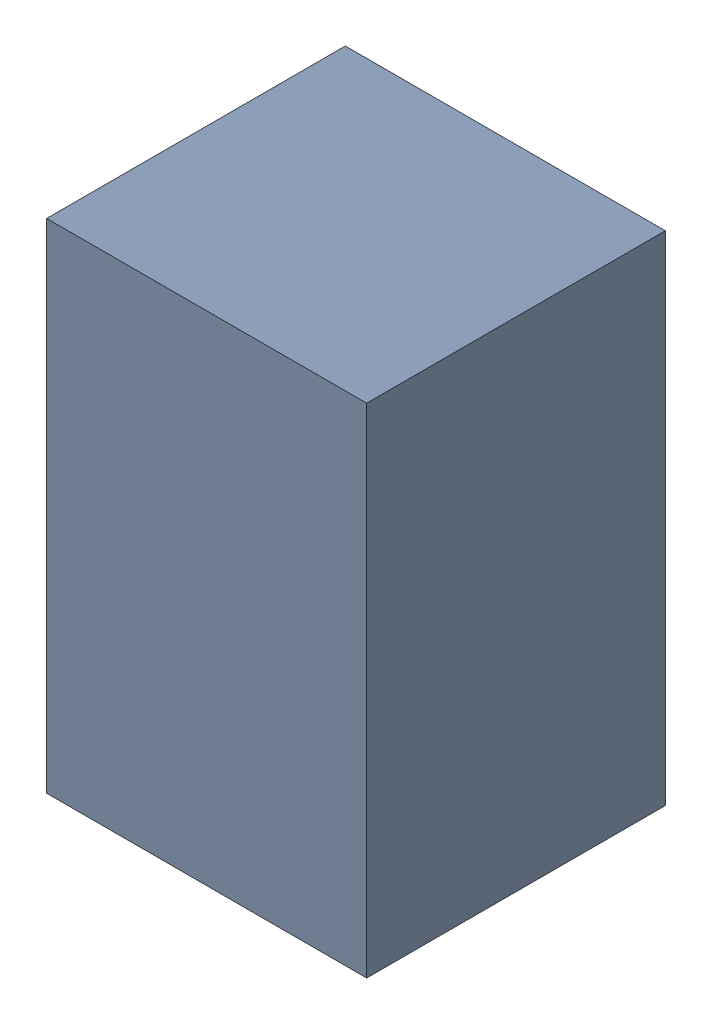
SolidWorks assembly CL1, configuration Default. Lengths in mm.
Overall size (1.35 2.1 1.26).
2 component instances, 1 part files, 0 mates.
Components (placement in the parent):
- 407985696-1: 407985696 [Default] at (30.734 69.723 0.0127) size (1.35 2.1 1.26)
  - Extruded_1-1: Extruded_1 [Default] at origin size (1.35 2.1 1.26)
